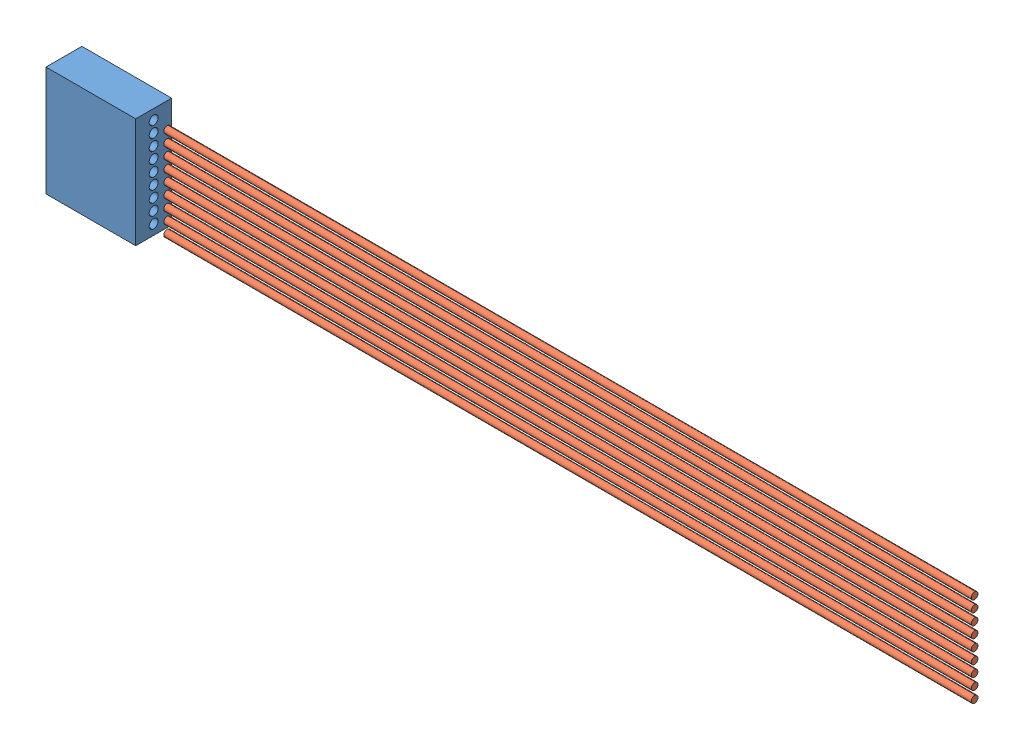
SolidWorks assembly Harness_26-CABLE_REALOP_ONE_ASSEMBLY, configuration AnnotateFlattenedRoute1 - Default. Lengths in mm.
Overall size (101.5 12.25 4).
3 component instances, 3 part files, 1 mates.
Components (placement in the parent):
- 9_PIN-1: 9_PIN [Default] at (-11.5 -10.9688 2) x (0 -1 0) z (1 0 0) size (12.25 4 20)
- Cable^Harness_26-CABLE_REALOP_ONE_ASSEMBLY-1: Cable^Harness_26-CABLE_REALOP_ONE_ASSEMBLY [Default] at origin size (10.75 2.25 0.75) (suppressed, hidden, virtual)
- Flattened_Cable^Harness_26-CABLE_REALOP_ONE_ASSEMBLY-1: Flattened_Cable^Harness_26-CABLE_REALOP_ONE_ASSEMBLY [Default] at origin (virtual)
Mates (geometry in assembly coordinates):
- Coincident1001: coincident anti-aligned: plane of Z_FACE_SOLAR_ARRAY-1 through (45.8255 8.7355 337.3251) normal (0 0 -1); plane of 9_PIN-1 through (4.3945 23.7355 337.3251) normal (0 0 1)
